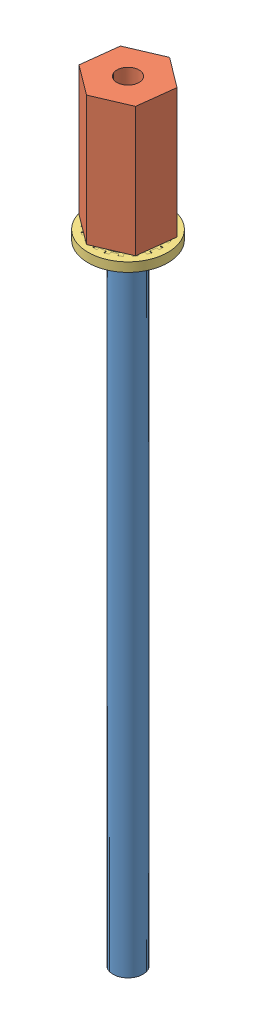
SolidWorks assembly OuterCurvatureFeedthrough, configuration Default. Lengths in mm.
Overall size (9.78 94.49 10.04).
3 component instances, 3 part files, 4 mates.
Components (placement in the parent):
- OuterCurvatureFeedthrough-1: OuterCurvatureFeedthrough [Default] at (-7.706 -33.6022 8.3446) size (3.68 83.69 3.68)
- CurrentConnector-1: CurrentConnector [Default] at (-7.706 45.0108 8.3446) x (0.118539 0 -0.992949) z (0.992949 0 0.118539) size (9.17 15.88 7.94)
- 93783A007_PRESSURE-SEALING WASHER FOR SCREWS AND BOLTS-1: 93783A007_PRESSURE-SEALING WASHER FOR SCREWS AND BOLTS [93783A007] at (-7.706 44.0609 8.3446) size (9.78 1.9 9.78)
Mates (geometry in assembly coordinates):
- Concentric1: concentric: cylinder of OuterCurvatureFeedthrough-1 through (-7.706 50.0908 8.3446) axis (0 -1 0) radius 1.8415; cylinder of CurrentConnector-1 through (-7.706 45.0108 8.3446) axis (0 -1 0) radius 1.3526
- Coincident1: coincident: plane of OuterCurvatureFeedthrough-1 through (-7.706 50.0908 8.3446) normal (0 1 0); circle of CurrentConnector-1
- Tangent5: tangent: plane of CurrentConnector-1 through (-7.706 45.0108 8.3446) normal (0 -1 0); torus of 93783A007_PRESSURE-SEALING WASHER FOR SCREWS AND BOLTS-1
- Concentric4: concentric: cylinder of OuterCurvatureFeedthrough-1 through (-7.706 50.0908 8.3446) axis (0 -1 0) radius 1.8415; cylinder of 93783A007_PRESSURE-SEALING WASHER FOR SCREWS AND BOLTS-1 through (-7.706 44.0609 8.3446) axis (0 -1 0) radius 4.8895
